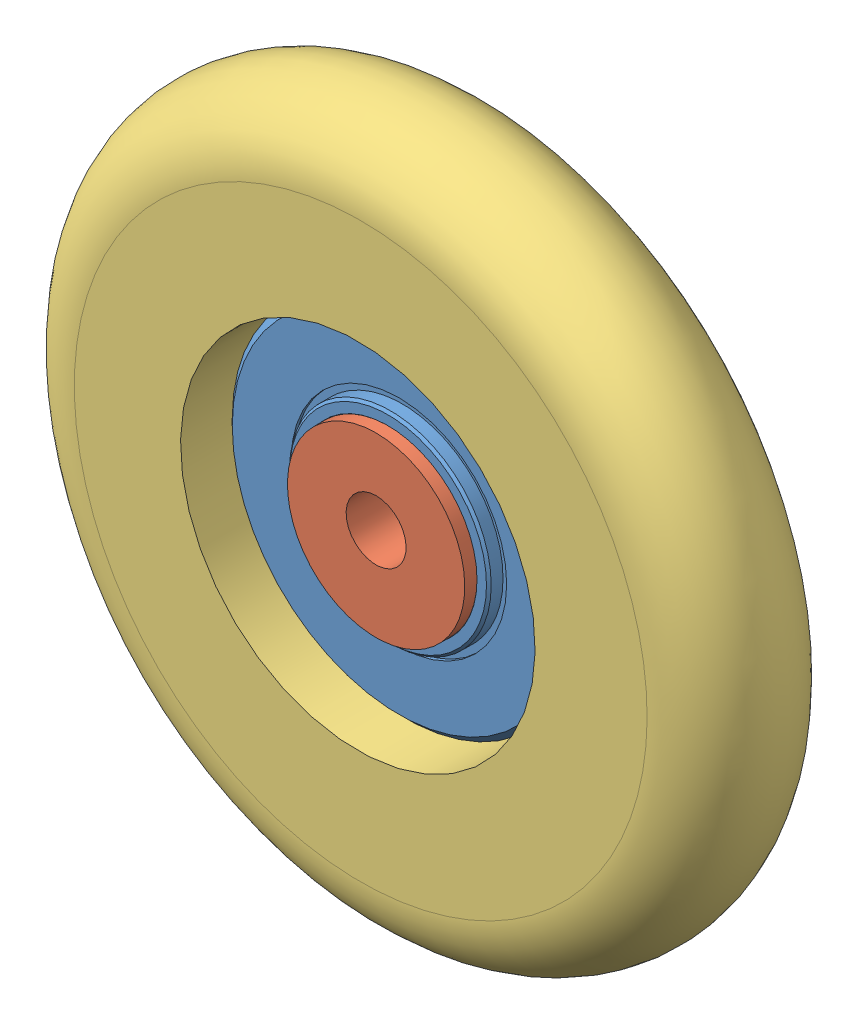
SolidWorks assembly Assemblage1, configuration Défaut. Lengths in mm.
Overall size (36.7 36.7 6.67).
3 component instances, 3 part files, 4 mates.
Components (placement in the parent):
- 57155K337_STAINLESS STEEL BALL BEARING-1: 57155K337_STAINLESS STEEL BALL BEARING [57155K337] at (-6.2675 2.207 13.8938) size (13.89 13.89 5.56)
- spacer-1: spacer [Défaut] at (-6.2675 2.207 11.1125) x (1 0 0) z (0 -1 0) size (6.5 6 6.5)
- wheel-1: wheel [Défaut] at (-6.1618 2.0878 12.7826) x (0.748328 0.663329 0) z (0.663329 -0.748328 0) size (26 5 26)
Mates (geometry in assembly coordinates):
- Coaxiale1: concentric anti-aligned: cylinder of 57155K337_STAINLESS STEEL BALL BEARING-1 through (-6.2675 2.207 16.2751) axis (0 0 1) radius 3.175; cylinder of spacer-1 through (-6.2675 2.207 17.1125) axis (0 0 -1) radius 3.25
- Coïncidente2: coincident aligned: plane of 57155K337_STAINLESS STEEL BALL BEARING-1 through (-6.2675 5.382 11.1125) normal (0 0 -1); plane of spacer-1 through (-6.2675 2.207 11.1125) normal (0 0 -1)
- Coaxiale3: concentric anti-aligned: cylinder of 57155K337_STAINLESS STEEL BALL BEARING-1 through (-6.2675 2.207 16.2751) axis (0 0 1) radius 6.35; cylinder of wheel-1 through (-6.2675 2.207 17.7826) axis (0 0 -1) radius 6.5
- Coïncidente4: coincident anti-aligned: plane of 57155K337_STAINLESS STEEL BALL BEARING-1 through (-6.2675 6.1567 12.7826) normal (0 0 1); plane of wheel-1 through (-6.1618 2.0878 12.7826) normal (0 0 -1)
